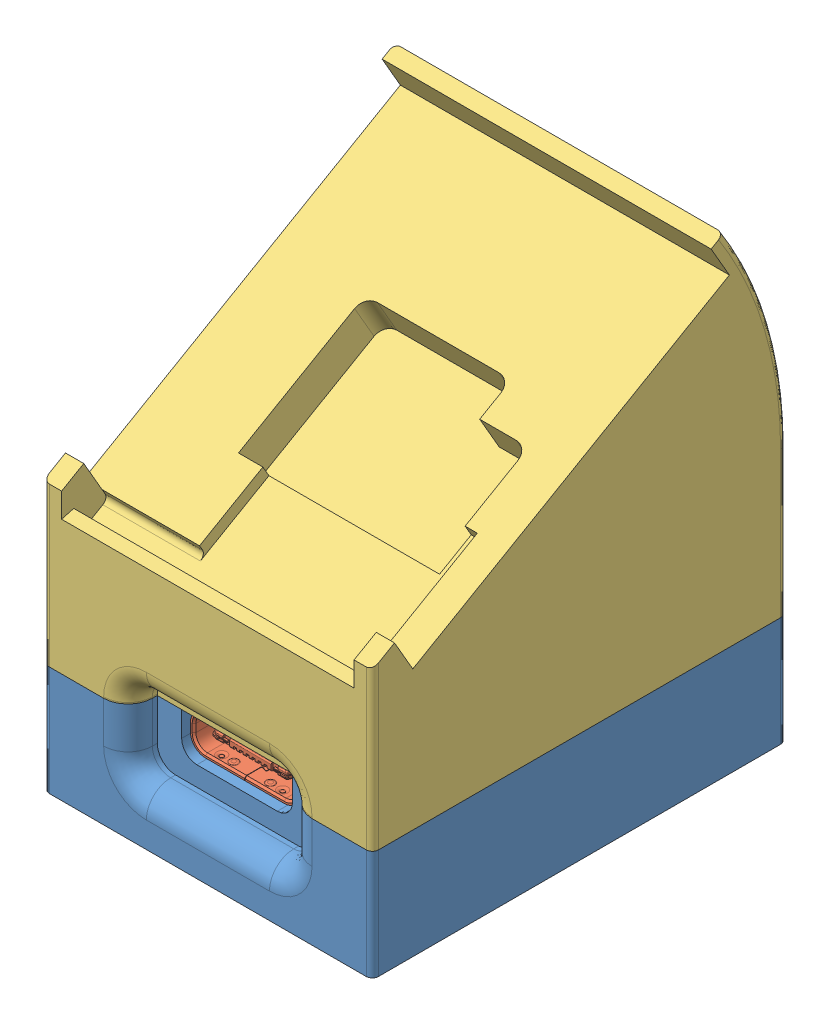
SolidWorks assembly 装配体1, configuration Default. Lengths in mm.
Overall size (27.06 38.68 34).
3 component instances, 3 part files, 9 mates.
Components (placement in the parent):
- LOWER_PART-1: LOWER_PART [默认] at (14.4968 15.8225 24.5704) size (27 9 34)
- MainBoard.step-1: MainBoard.step [默认] at (1.3523 21.63 8.1621) x (0 0 1) z (0 1 0) size (29.49 23.87 11.19)
- UPPER_PART-1: UPPER_PART [默认] at (27.9968 24.8225 7.5704) x (-1 0 0) z (0 1 0) size (27.06 34 29.68)
Mates (geometry in assembly coordinates):
- 平行3: parallel aligned: plane of LOWER_PART-1 through (14.4968 24.8225 24.5704) normal (0 1 0); plane of MainBoard.step-1 through (10.9943 21.63 14.0651) normal (0 1 0)
- 平行4: parallel aligned: plane of LOWER_PART-1 through (0.9968 24.8225 41.5704) normal (0 0 1); plane of MainBoard.step-1 through (20.4653 20.3263 35.3401) normal (0 0 1)
- 宽度2: width anti-aligned: plane of LOWER_PART-1 through (27.9968 24.8225 41.5704) normal (1 0 0); plane of LOWER_PART-1 through (0.9968 24.8225 41.5704) normal (-1 0 0); plane of MainBoard.step-1 through (2.7493 20.3263 15.3271) normal (-1 0 0); plane of MainBoard.step-1 through (26.2443 20.3263 33.3081) normal (1 0 0)
- 平行6: parallel aligned: plane of LOWER_PART-1 through (0.9968 24.8225 41.5704) normal (-1 0 0); plane of UPPER_PART-1 through (0.9968 36.8225 40.3295) normal (-1 0 0)
- 平行7: parallel aligned: plane of LOWER_PART-1 through (0.9968 24.8225 41.5704) normal (0 0 1); plane of UPPER_PART-1 through (0.9968 24.8225 41.5704) normal (0 0 1)
- 重合2: coincident anti-aligned: plane of LOWER_PART-1 through (14.4968 24.8225 24.5704) normal (0 1 0); plane of UPPER_PART-1 through (0.9968 24.8225 7.5704) normal (0 -1 0)
- 重合3: coincident aligned: plane of LOWER_PART-1 through (0.9968 24.8225 41.5704) normal (-1 0 0); plane of UPPER_PART-1 through (0.9968 36.8225 40.3295) normal (-1 0 0)
- 重合4: coincident aligned: plane of LOWER_PART-1 through (0.9968 24.8225 41.5704) normal (0 0 1); plane of UPPER_PART-1 through (0.9968 24.8225 41.5704) normal (0 0 1)
- 距离1: distance = 0.3 mm anti-aligned: plane of LOWER_PART-1 through (10.7718 19.3225 8.7511) normal (0 0 1); plane of MainBoard.step-1 through (17.8573 20.3263 9.0511) normal (0 0 -1)
